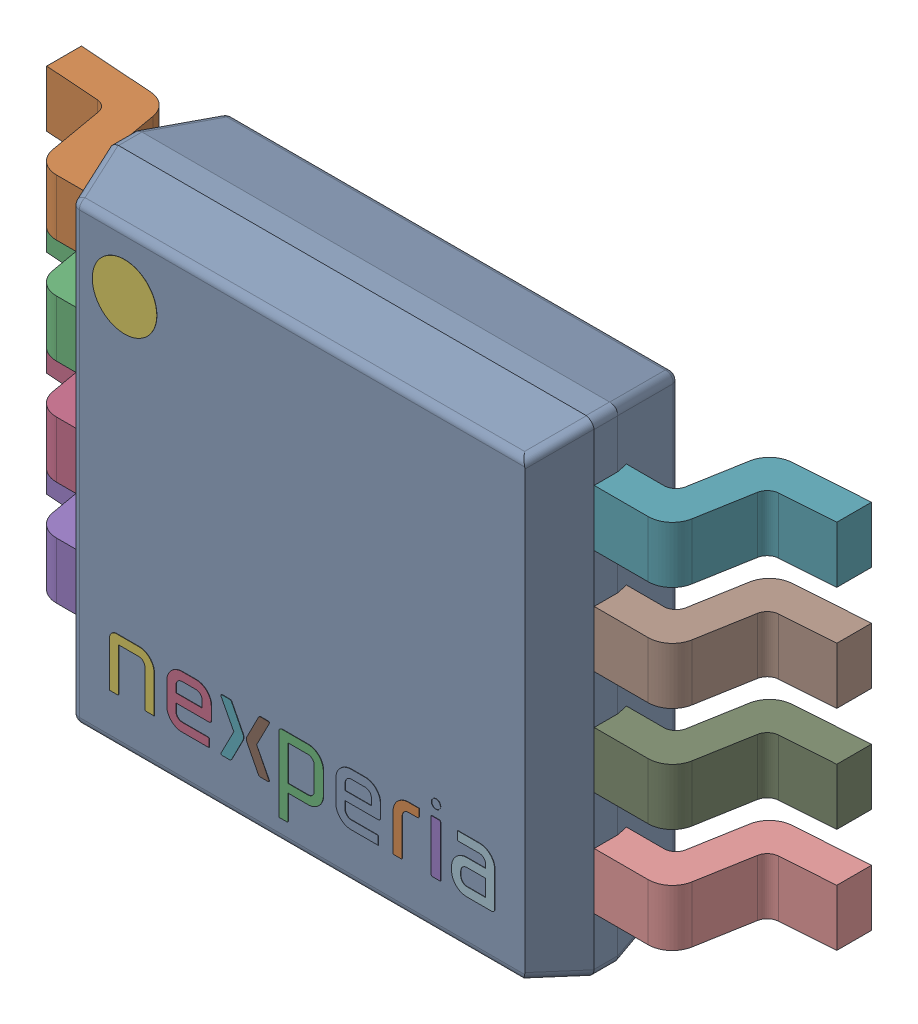
SolidWorks assembly IC_NXP_Semiconductors_PCA9517DP_118_eec, configuration Default. Lengths in mm.
Overall size (4.9 3 1.12).
11 component instances, 5 part files, 0 mates.
Components (placement in the parent):
- IC_BODY-1: IC_BODY [Default] at (0 0 0.15) x (0 -1 0) z (0 0 1) size (3 3 0.97)
- IC_LEG-1: IC_LEG [Default] at (-2.45 1.1495 0) x (1 0 0) z (0 -1 0) size (1.05 0.77 0.35)
- IC_LEG-2: IC_LEG [Default] at (-2.45 0.4995 0) x (1 0 0) z (0 -1 0) size (1.05 0.77 0.35)
- IC_LEG-3: IC_LEG [Default] at (-2.45 -0.1505 0) x (1 0 0) z (0 -1 0) size (1.05 0.77 0.35)
- IC_LEG-4: IC_LEG [Default] at (-2.45 -0.8005 0) x (1 0 0) z (0 -1 0) size (1.05 0.77 0.35)
- circle-1: circle [Default] at (-1.0817 1.037 1.101) x (1 0 0) z (0 0 -1) size (0.4 0.4 0.01)
- IC_LEG_MIR5-1: IC_LEG_MIR5 [Default] at (2.45 1.1495 0) x (-1 0 0) z (0 1 0) size (1.05 0.77 0.35)
- IC_LEG_MIR5-2: IC_LEG_MIR5 [Default] at (2.45 0.4995 0) x (-1 0 0) z (0 1 0) size (1.05 0.77 0.35)
- IC_LEG_MIR5-3: IC_LEG_MIR5 [Default] at (2.45 -0.1505 0) x (-1 0 0) z (0 1 0) size (1.05 0.77 0.35)
- IC_LEG_MIR5-4: IC_LEG_MIR5 [Default] at (2.45 -0.8005 0) x (-1 0 0) z (0 1 0) size (1.05 0.77 0.35)
- Nexperia-1: Nexperia [Default] at (-0.092 -0.9859 1.1) size (2.4 0.59 0.04)
